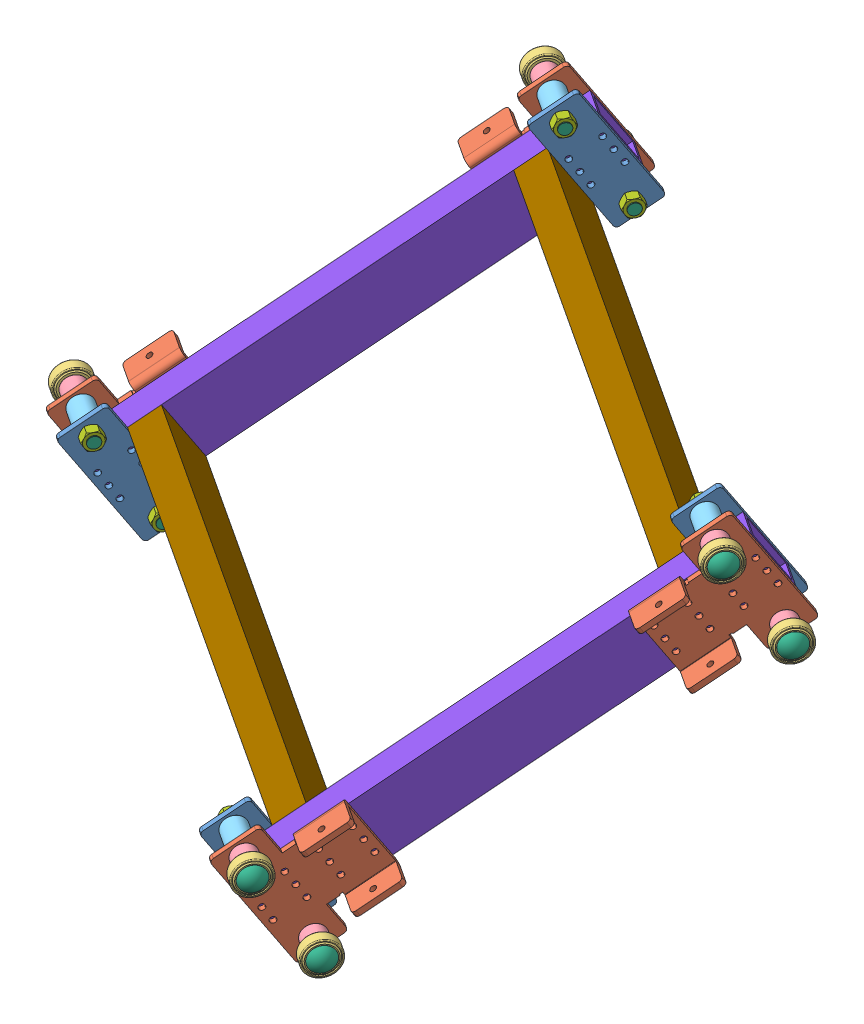
SolidWorks assembly carrige assembly, configuration Default. Lengths in mm.
Overall size (674.12 304.18 625.69).
56 component instances, 9 part files, 24 mates.
Components (placement in the parent):
- Roller-2: Roller [Défaut] at (216.4337 91.5152 515.3608) x (-0.299148 0.837169 0.457885) z (0.457885 0.546944 -0.700852) size (108.2 74.88 88.9)
  - am3793a-1: am3793a [Défaut] at (0 -30.16 0) size (101.6 4.76 38.1)
  - am3794a-1: am3794a [Défaut] at origin size (101.6 25 88.9)
  - am-0209b-1: am-0209b [Défaut] at (-39.8145 20.6375 0) x (1 0 0) z (0 1 0) size (28.57 28.57 9.53)
  - am1451-1: am1451 [Défaut] at (-39.8145 7.9375 0) x (0 0 1) z (-1 0 0) size (19.05 15.88 19.05)
  - am1451-2: am1451 [Défaut] at (39.8145 7.9375 0) x (-1 0 0) z (0 0 -1) size (19.05 15.88 19.05)
  - am-0209b-3: am-0209b [Défaut] at (39.8145 20.6375 0) x (1 0 0) z (0 1 0) size (28.57 28.57 9.53)
  - am1450-1: am1450 [Défaut] at (-39.8145 -17.46 0) size (19.05 25.4 19.05)
  - am1450-2: am1450 [Défaut] at (39.8145 -17.46 0) size (19.05 25.4 19.05)
  - round head bolt_ai-2: round head bolt_ai [RHBOLT 0.375-16x2.75x1-C] at (-39.8145 30.4292 0) x (0 -1 0) z (-1 0 0) size (74.88 20.65 20.65)
  - round head bolt_ai-3: round head bolt_ai [RHBOLT 0.375-16x2.75x1-C] at (39.8145 30.4292 0) x (0 -1 0) z (-1 0 0) size (74.88 20.65 20.65)
  - hex nut_ai-1: hex nut_ai [HNUT 0.3750-16-D-N] at (39.8145 -43.4798 0) x (0 0 1) z (0 -1 0) size (14.27 16.48 8.56)
  - hex nut_ai-2: hex nut_ai [HNUT 0.3750-16-D-N] at (-39.8145 -43.4798 0) x (0 0 1) z (0 -1 0) size (14.27 16.48 8.56)
- Roller-3: Roller [Défaut] at (-195.5539 91.5152 246.1986) x (0.299148 -0.837169 -0.457885) z (0.457885 0.546944 -0.700852) size (108.2 74.88 88.9)
  - am3793a-1: am3793a [Défaut] at (0 -30.16 0) size (101.6 4.76 38.1)
  - am3794a-1: am3794a [Défaut] at origin size (101.6 25 88.9)
  - am-0209b-1: am-0209b [Défaut] at (-39.8145 20.6375 0) x (1 0 0) z (0 1 0) size (28.57 28.57 9.53)
  - am1451-1: am1451 [Défaut] at (-39.8145 7.9375 0) x (0 0 1) z (-1 0 0) size (19.05 15.88 19.05)
  - am1451-2: am1451 [Défaut] at (39.8145 7.9375 0) x (-1 0 0) z (0 0 -1) size (19.05 15.88 19.05)
  - am-0209b-3: am-0209b [Défaut] at (39.8145 20.6375 0) x (1 0 0) z (0 1 0) size (28.57 28.57 9.53)
  - am1450-1: am1450 [Défaut] at (-39.8145 -17.46 0) size (19.05 25.4 19.05)
  - am1450-2: am1450 [Défaut] at (39.8145 -17.46 0) size (19.05 25.4 19.05)
  - round head bolt_ai-2: round head bolt_ai [RHBOLT 0.375-16x2.75x1-C] at (-39.8145 30.4292 0) x (0 -1 0) z (-1 0 0) size (74.88 20.65 20.65)
  - round head bolt_ai-3: round head bolt_ai [RHBOLT 0.375-16x2.75x1-C] at (39.8145 30.4292 0) x (0 -1 0) z (-1 0 0) size (74.88 20.65 20.65)
  - hex nut_ai-1: hex nut_ai [HNUT 0.3750-16-D-N] at (39.8145 -43.4798 0) x (0 0 1) z (0 -1 0) size (14.27 16.48 8.56)
  - hex nut_ai-2: hex nut_ai [HNUT 0.3750-16-D-N] at (-39.8145 -43.4798 0) x (0 0 1) z (0 -1 0) size (14.27 16.48 8.56)
- Roller-4: Roller [Défaut] at (377.8038 284.272 268.363) x (0.299148 -0.837169 -0.457885) z (-0.457885 -0.546944 0.700852) size (108.2 74.88 88.9)
  - am3793a-1: am3793a [Défaut] at (0 -30.16 0) size (101.6 4.76 38.1)
  - am3794a-1: am3794a [Défaut] at origin size (101.6 25 88.9)
  - am-0209b-1: am-0209b [Défaut] at (-39.8145 20.6375 0) x (1 0 0) z (0 1 0) size (28.57 28.57 9.53)
  - am1451-1: am1451 [Défaut] at (-39.8145 7.9375 0) x (0 0 1) z (-1 0 0) size (19.05 15.88 19.05)
  - am1451-2: am1451 [Défaut] at (39.8145 7.9375 0) x (-1 0 0) z (0 0 -1) size (19.05 15.88 19.05)
  - am-0209b-3: am-0209b [Défaut] at (39.8145 20.6375 0) x (1 0 0) z (0 1 0) size (28.57 28.57 9.53)
  - am1450-1: am1450 [Défaut] at (-39.8145 -17.46 0) size (19.05 25.4 19.05)
  - am1450-2: am1450 [Défaut] at (39.8145 -17.46 0) size (19.05 25.4 19.05)
  - round head bolt_ai-2: round head bolt_ai [RHBOLT 0.375-16x2.75x1-C] at (-39.8145 30.4292 0) x (0 -1 0) z (-1 0 0) size (74.88 20.65 20.65)
  - round head bolt_ai-3: round head bolt_ai [RHBOLT 0.375-16x2.75x1-C] at (39.8145 30.4292 0) x (0 -1 0) z (-1 0 0) size (74.88 20.65 20.65)
  - hex nut_ai-1: hex nut_ai [HNUT 0.3750-16-D-N] at (39.8145 -43.4798 0) x (0 0 1) z (0 -1 0) size (14.27 16.48 8.56)
  - hex nut_ai-2: hex nut_ai [HNUT 0.3750-16-D-N] at (-39.8145 -43.4798 0) x (0 0 1) z (0 -1 0) size (14.27 16.48 8.56)
- Roller-5: Roller [Défaut] at (-34.1839 284.272 -0.7992) x (-0.299148 0.837169 0.457885) z (-0.457885 -0.546944 0.700852) size (108.2 74.88 88.9)
  - am3793a-1: am3793a [Défaut] at (0 -30.16 0) size (101.6 4.76 38.1)
  - am3794a-1: am3794a [Défaut] at origin size (101.6 25 88.9)
  - am-0209b-1: am-0209b [Défaut] at (-39.8145 20.6375 0) x (1 0 0) z (0 1 0) size (28.57 28.57 9.53)
  - am1451-1: am1451 [Défaut] at (-39.8145 7.9375 0) x (0 0 1) z (-1 0 0) size (19.05 15.88 19.05)
  - am1451-2: am1451 [Défaut] at (39.8145 7.9375 0) x (-1 0 0) z (0 0 -1) size (19.05 15.88 19.05)
  - am-0209b-3: am-0209b [Défaut] at (39.8145 20.6375 0) x (1 0 0) z (0 1 0) size (28.57 28.57 9.53)
  - am1450-1: am1450 [Défaut] at (-39.8145 -17.46 0) size (19.05 25.4 19.05)
  - am1450-2: am1450 [Défaut] at (39.8145 -17.46 0) size (19.05 25.4 19.05)
  - round head bolt_ai-2: round head bolt_ai [RHBOLT 0.375-16x2.75x1-C] at (-39.8145 30.4292 0) x (0 -1 0) z (-1 0 0) size (74.88 20.65 20.65)
  - round head bolt_ai-3: round head bolt_ai [RHBOLT 0.375-16x2.75x1-C] at (39.8145 30.4292 0) x (0 -1 0) z (-1 0 0) size (74.88 20.65 20.65)
  - hex nut_ai-1: hex nut_ai [HNUT 0.3750-16-D-N] at (39.8145 -43.4798 0) x (0 0 1) z (0 -1 0) size (14.27 16.48 8.56)
  - hex nut_ai-2: hex nut_ai [HNUT 0.3750-16-D-N] at (-39.8145 -43.4798 0) x (0 0 1) z (0 -1 0) size (14.27 16.48 8.56)
- 15 3 8 height-1: 15 3 8 height [Default] at (190.0604 59.8318 500.5859) x (-0.299148 0.837169 0.457885) z (-0.837169 0 -0.546944) size (50.8 390.53 25.4)
- 15 3 8 height-2: 15 3 8 height [Default] at (-186.626 102.36 287.676) x (0.299148 -0.837169 -0.457885) z (0.837169 0 0.546944) size (50.8 390.53 25.4)
- 16 3 4 Width-1: 16 3 4 Width [Default] at (336.2337 295.1168 276.8487) x (0.299148 -0.837169 -0.457885) z (0.457885 0.546944 -0.700852) size (50.8 431.8 25.4)
- 16 3 4 Width-2: 16 3 4 Width [Default] at (-169.1806 123.1985 260.9735) x (0.299148 -0.837169 -0.457885) z (-0.457885 -0.546944 0.700852) size (50.8 431.8 25.4)
Mates (geometry in assembly coordinates):
- Coincident6: coincident anti-aligned: plane of Roller-5/am3794a-1 through (-30.199 284.272 1.8043) normal (0.837169 0 0.546944); plane of 15 3 8 height-2 through (-29.0746 315.9553 0.0833) normal (-0.837169 0 -0.546944)
- Coincident7: coincident aligned: plane of Roller-5/am3794a-1 through (-31.3233 252.5886 3.5253) normal (0.299148 -0.837169 -0.457885); plane of 15 3 8 height-2 through (7.3862 273.4271 -9.2848) normal (0.299148 -0.837169 -0.457885)
- Coincident8: coincident aligned: plane of Roller-5/am3793a-1 through (-11.424 337.2194 28.2094) normal (0.457885 0.546944 -0.700852); plane of 15 3 8 height-2 through (-7.8105 315.9553 13.9757) normal (0.457885 0.546944 -0.700852)
- Coincident9: coincident anti-aligned: plane of Roller-3/am3794a-1 through (-191.569 91.5152 248.8021) normal (0.837169 0 0.546944); plane of 15 3 8 height-2 through (-29.0746 315.9553 0.0833) normal (-0.837169 0 -0.546944)
- Coincident10: coincident aligned: plane of Roller-3/am3794a-1 through (-175.2479 80.6704 223.8206) normal (0.299148 -0.837169 -0.457885); plane of 15 3 8 height-2 through (7.3862 273.4271 -9.2848) normal (0.299148 -0.837169 -0.457885)
- Coincident11: coincident aligned: plane of Roller-3/am3794a-1 through (-185.095 38.5677 238.8928) normal (-0.457885 -0.546944 0.700852); plane of 15 3 8 height-2 through (-186.626 102.36 287.676) normal (-0.457885 -0.546944 0.700852)
- Coincident12: coincident anti-aligned: plane of Roller-4/am3794a-1 through (373.8188 284.272 265.7595) normal (-0.837169 0 -0.546944); plane of 15 3 8 height-1 through (390.1399 273.4271 240.778) normal (0.837169 0 0.546944)
- Coincident13: coincident aligned: plane of Roller-4/am3794a-1 through (372.6945 252.5886 267.4805) normal (0.299148 -0.837169 -0.457885); plane of 15 3 8 height-1 through (368.8758 273.4271 226.8856) normal (0.299148 -0.837169 -0.457885)
- Coincident14: coincident aligned: plane of Roller-4/am3794a-1 through (397.7383 252.163 229.1478) normal (0.457885 0.546944 -0.700852); plane of 15 3 8 height-1 through (368.8758 273.4271 226.8856) normal (0.457885 0.546944 -0.700852)
- Coincident15: coincident anti-aligned: plane of Roller-2/am3793a-1 through (191.1847 91.5152 498.865) normal (0.837169 0 0.546944); plane of 15 3 8 height-1 through (368.8758 273.4271 226.8856) normal (-0.837169 0 -0.546944)
- Coincident16: coincident aligned: plane of Roller-2/am3794a-1 through (188.5294 123.6241 549.3691) normal (-0.457885 -0.546944 0.700852); plane of 15 3 8 height-1 through (190.0604 59.8318 500.5859) normal (-0.457885 -0.546944 0.700852)
- Coincident17: coincident aligned: plane of Roller-2/am3794a-1 through (228.7699 80.6704 487.7758) normal (0.299148 -0.837169 -0.457885); plane of 15 3 8 height-1 through (368.8758 273.4271 226.8856) normal (0.299148 -0.837169 -0.457885)
- Coincident18: coincident anti-aligned: plane of 15 3 8 height-2 through (-7.8105 315.9553 13.9757) normal (0.837169 0 0.546944); plane of 16 3 4 Width-1 through (-25.2559 295.1168 40.6782) normal (-0.837169 0 -0.546944)
- Coincident19: coincident aligned: plane of 15 3 8 height-2 through (7.3862 273.4271 -9.2848) normal (0.299148 -0.837169 -0.457885); plane of 16 3 4 Width-1 through (-10.0592 252.5886 17.4176) normal (0.299148 -0.837169 -0.457885)
- Coincident20: coincident anti-aligned: plane of Roller-5/am3793a-1 through (-28.8694 316.3809 54.9119) normal (-0.457885 -0.546944 0.700852); plane of 16 3 4 Width-1 through (-25.2559 295.1168 40.6782) normal (0.457885 0.546944 -0.700852)
- Coincident21: coincident anti-aligned: plane of 15 3 8 height-1 through (368.8758 273.4271 226.8856) normal (-0.837169 0 -0.546944); plane of 16 3 4 Width-1 through (336.2337 295.1168 276.8487) normal (0.837169 0 0.546944)
- Coincident22: coincident aligned: plane of 15 3 8 height-1 through (368.8758 273.4271 226.8856) normal (0.299148 -0.837169 -0.457885); plane of 16 3 4 Width-1 through (-10.0592 252.5886 17.4176) normal (0.299148 -0.837169 -0.457885)
- Coincident23: coincident anti-aligned: plane of Roller-4/am3793a-1 through (355.0438 231.3245 239.3544) normal (-0.457885 -0.546944 0.700852); plane of 16 3 4 Width-1 through (-25.2559 295.1168 40.6782) normal (0.457885 0.546944 -0.700852)
- Coincident24: coincident anti-aligned: plane of 15 3 8 height-1 through (368.8758 273.4271 226.8856) normal (-0.837169 0 -0.546944); plane of 16 3 4 Width-2 through (192.3091 123.1985 497.144) normal (0.837169 0 0.546944)
- Coincident25: coincident anti-aligned: plane of Roller-2/am3793a-1 through (180.7258 144.4626 506.1708) normal (0.457885 0.546944 -0.700852); plane of 16 3 4 Width-2 through (192.3091 123.1985 497.144) normal (-0.457885 -0.546944 0.700852)
- Coincident26: coincident aligned: plane of 15 3 8 height-1 through (353.6791 315.9553 250.1462) normal (-0.299148 0.837169 0.457885); plane of 16 3 4 Width-2 through (192.3091 123.1985 497.144) normal (-0.299148 0.837169 0.457885)
- Coincident27: coincident anti-aligned: plane of 15 3 8 height-2 through (-7.8105 315.9553 13.9757) normal (0.837169 0 0.546944); plane of 16 3 4 Width-2 through (-169.1806 123.1985 260.9735) normal (-0.837169 0 -0.546944)
- Coincident28: coincident aligned: plane of 15 3 8 height-2 through (-7.8105 315.9553 13.9757) normal (-0.299148 0.837169 0.457885); plane of 16 3 4 Width-2 through (192.3091 123.1985 497.144) normal (-0.299148 0.837169 0.457885)
- Coincident29: coincident anti-aligned: plane of Roller-3/am3793a-1 through (-142.4006 59.4063 228.6862) normal (0.457885 0.546944 -0.700852); plane of 16 3 4 Width-2 through (192.3091 123.1985 497.144) normal (-0.457885 -0.546944 0.700852)
